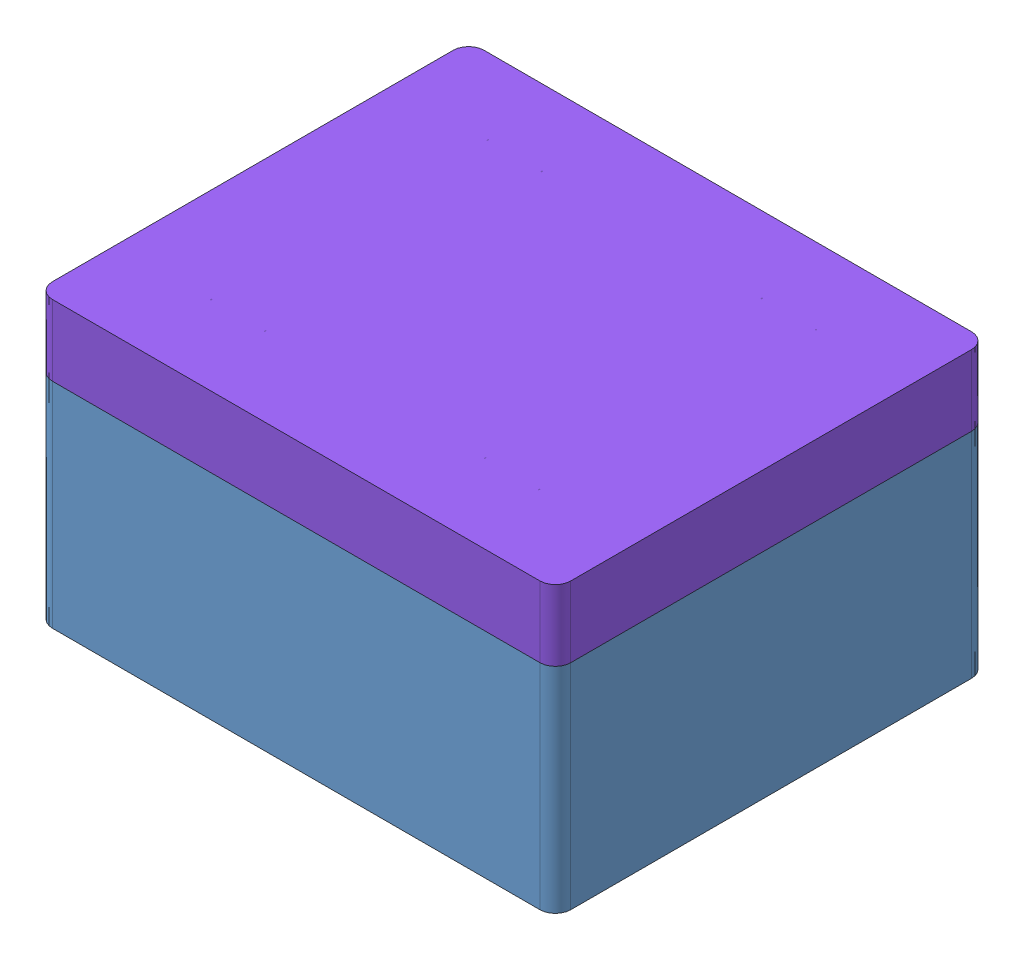
SolidWorks assembly LCA_Baseline_Enclosure_16122020, configuration Default. Lengths in mm.
Overall size (428.6 235.47 356.89).
8 component instances, 8 part files, 23 mates.
Components (placement in the parent):
- 1507 Bottom Tub-1: 1507 Bottom Tub [Default] at (199.2394 311.5225 306.9874) size (428.6 178.19 356.89)
- Back_Plate-1: Back_Plate [Default] at (199.2394 146.6765 306.9874) size (355.6 12.7 254)
- 8961K93_MOUNTING ADAPTERS FOR DIN RAIL-2-1: 8961K93_MOUNTING ADAPTERS FOR DIN RAIL-2 [8961K93] at (377.0394 159.3765 306.9874) x (0 -1 0) z (-1 0 0) size (7.5 35 355.6)
- 8961K107_MOUNTING ADAPTERS FOR DIN RAIL-1: 8961K107_MOUNTING ADAPTERS FOR DIN RAIL [8961K107] at (247.9771 169.3765 281.8198) x (0 1 0) z (-1 0 0) size (8 51.36 75)
- BaselineSpeedgoat-1: BaselineSpeedgoat [Default] at (192.9771 169.3765 270.6428) x (0 0 1) z (-1 0 0) size (200 130 190)
- LoadCellAmplifier-1: LoadCellAmplifier [Default] at (36.9078 238.5439 298.0974) x (-0.034899 0.999391 0) z (0.999391 0.034899 0) size (110.24 17.78 89.92)
- 8961K93_MOUNTING ADAPTERS FOR DIN RAIL 6in-1: 8961K93_MOUNTING ADAPTERS FOR DIN RAIL 6in [8961K93] at (4.1417 237.3997 383.1874) x (-0.999391 -0.034899 0) z (0 0 -1) size (7.5 35 152.4)
- 1507 Top Tub-1: 1507 Top Tub [Default] at (199.2394 311.5225 306.9874) size (428.6 59.13 356.89)
Mates (geometry in assembly coordinates):
- Coincident1: coincident anti-aligned: plane of 1507 Bottom Tub-1 through (63.4463 146.6765 182.6385) normal (0 1 0); plane of Back_Plate-1 through (199.2394 146.6765 306.9874) normal (0 -1 0)
- Width1: width aligned: plane of Back_Plate-1 through (21.4394 159.3765 179.9874) normal (-1 0 0); plane of Back_Plate-1 through (377.0394 159.3765 179.9874) normal (1 0 0); plane of 1507 Bottom Tub-1 through (1.794 304.6275 306.9874) normal (0.999391 0.034899 0); plane of 1507 Bottom Tub-1 through (396.6848 304.6275 306.9874) normal (-0.999391 0.034899 0)
- Width2: width anti-aligned: plane of Back_Plate-1 through (21.4394 159.3765 433.9874) normal (0 0 1); plane of Back_Plate-1 through (21.4394 159.3765 179.9874) normal (0 0 -1); plane of 1507 Bottom Tub-1 through (199.2394 306.2992 157.4134) normal (0 0.034899 0.999391); plane of 1507 Bottom Tub-1 through (199.2394 306.2992 456.5613) normal (0 0.034899 -0.999391)
- Coincident2: coincident anti-aligned: plane of Back_Plate-1 through (199.2394 159.3765 306.9874) normal (0 1 0); plane of 8961K93_MOUNTING ADAPTERS FOR DIN RAIL-2-1 through (-72.2231 159.3765 293.4874) normal (0 -1 0)
- Width3: width aligned: plane of 8961K93_MOUNTING ADAPTERS FOR DIN RAIL-2-1 through (377.0394 159.3765 306.9874) normal (1 0 0); plane of 8961K93_MOUNTING ADAPTERS FOR DIN RAIL-2-1 through (21.4394 159.3765 306.9874) normal (-1 0 0); plane of 1507 Bottom Tub-1 through (396.6848 304.6275 306.9874) normal (-0.999391 0.034899 0); plane of 1507 Bottom Tub-1 through (1.794 304.6275 306.9874) normal (0.999391 0.034899 0)
- Width4: width anti-aligned: plane of 8961K107_MOUNTING ADAPTERS FOR DIN RAIL-1 through (247.9771 163.0307 281.8198) normal (0 0 -1); plane of 8961K107_MOUNTING ADAPTERS FOR DIN RAIL-1 through (247.9771 165.6765 332.1549) normal (0 0 1); plane of 8961K93_MOUNTING ADAPTERS FOR DIN RAIL-2-1 through (-72.2231 166.8765 324.4874) normal (0 0 1); plane of 8961K93_MOUNTING ADAPTERS FOR DIN RAIL-2-1 through (-72.2231 165.8765 289.4874) normal (0 0 -1)
- Coincident3: coincident anti-aligned: plane of 8961K93_MOUNTING ADAPTERS FOR DIN RAIL-2-1 through (-72.2231 166.8765 320.4874) normal (0 1 0); plane of 8961K107_MOUNTING ADAPTERS FOR DIN RAIL-1 through (247.9771 166.8765 321.4049) normal (0 -1 0)
- Coincident4: coincident anti-aligned: plane of 8961K107_MOUNTING ADAPTERS FOR DIN RAIL-1 through (247.9771 169.3765 282.0698) normal (0 1 0); plane of BaselineSpeedgoat-1 through (192.9771 169.3765 270.6428) normal (0 -1 0)
- Perpendicular1: perpendicular: plane of 1507 Bottom Tub-1 through (199.2394 306.2992 157.4134) normal (0 0.034899 0.999391); plane of BaselineSpeedgoat-1 through (152.9771 299.3765 212.9874) normal (-1 0 0)
- Coincident6: coincident anti-aligned: plane of 8961K107_MOUNTING ADAPTERS FOR DIN RAIL-1 through (247.9771 169.3765 282.0698) normal (0 1 0); plane of BaselineSpeedgoat-1 through (192.9771 169.3765 270.6428) normal (0 -1 0)
- Width6: width anti-aligned: plane of BaselineSpeedgoat-1 through (342.9771 299.3765 402.9874) normal (0 0 1); plane of BaselineSpeedgoat-1 through (192.9771 169.3765 210.9874) normal (0 0 -1); plane of 1507 Bottom Tub-1 through (199.2394 306.2992 157.4134) normal (0 0.034899 0.999391); plane of 1507 Bottom Tub-1 through (199.2394 306.2992 456.5613) normal (0 0.034899 -0.999391)
- Width7: width aligned: plane of 8961K93_MOUNTING ADAPTERS FOR DIN RAIL-2-1 through (-72.2231 166.8765 324.4874) normal (0 0 1); plane of 8961K93_MOUNTING ADAPTERS FOR DIN RAIL-2-1 through (-72.2231 165.8765 289.4874) normal (0 0 -1); plane of 1507 Bottom Tub-1 through (199.2394 306.2992 456.5613) normal (0 0.034899 -0.999391); plane of 1507 Bottom Tub-1 through (199.2394 306.2992 157.4134) normal (0 0.034899 0.999391)
- Width8: width anti-aligned: plane of 8961K107_MOUNTING ADAPTERS FOR DIN RAIL-1 through (210.4771 166.4764 308.0981) normal (-1 0 0); plane of 8961K107_MOUNTING ADAPTERS FOR DIN RAIL-1 through (285.4771 166.4764 308.0981) normal (1 0 0); plane of BaselineSpeedgoat-1 through (342.9771 299.3765 212.9874) normal (1 0 0); plane of BaselineSpeedgoat-1 through (152.9771 299.3765 212.9874) normal (-1 0 0)
- Width9: width aligned: plane of 8961K93_MOUNTING ADAPTERS FOR DIN RAIL 6in-1 through (4.1417 237.3997 383.1874) normal (0 0 1); plane of 8961K93_MOUNTING ADAPTERS FOR DIN RAIL 6in-1 through (4.1417 237.3997 230.7874) normal (0 0 -1); plane of 1507 Bottom Tub-1 through (199.2394 306.2992 456.5613) normal (0 0.034899 -0.999391); plane of 1507 Bottom Tub-1 through (199.2394 306.2992 157.4134) normal (0 0.034899 0.999391)
- Coincident9: coincident anti-aligned: plane of 1507 Bottom Tub-1 through (199.2394 311.5225 306.9874) normal (0 1 0); plane of 1507 Top Tub-1 through (199.2394 311.5225 306.9874) normal (0 -1 0)
- Width12: width anti-aligned: plane of 1507 Top Tub-1 through (413.538 331.8425 129.797) normal (1 0 0); plane of 1507 Bottom Tub-1 through (-15.0592 331.8425 486.6911) normal (-1 0 0); plane of 1507 Top Tub-1 through (-15.0592 291.2025 129.797) normal (-1 0 0); plane of 1507 Bottom Tub-1 through (413.538 291.2025 486.6911) normal (1 0 0)
- Width13: width anti-aligned: plane of 1507 Top Tub-1 through (-15.0592 331.8425 129.797) normal (0 0 -1); plane of 1507 Bottom Tub-1 through (413.538 331.8425 486.6911) normal (0 0 1); plane of 1507 Top Tub-1 through (-15.0592 291.2025 486.6911) normal (0 0 1); plane of 1507 Bottom Tub-1 through (413.538 291.2025 129.797) normal (0 0 -1)
- Width19: width aligned: plane of LoadCellAmplifier-1 through (36.9078 238.5439 298.0974) normal (0 0 -1); plane of 8961K93_MOUNTING ADAPTERS FOR DIN RAIL 6in-1 through (36.9078 238.5439 315.8774) normal (0 0 1); plane of LoadCellAmplifier-1 through (4.1417 237.3997 230.7874) normal (0 0 -1); plane of 8961K93_MOUNTING ADAPTERS FOR DIN RAIL 6in-1 through (4.1417 237.3997 383.1874) normal (0 0 1)
- Coincident19: coincident anti-aligned: plane of LoadCellAmplifier-1 through (13.5607 182.577 315.8774) normal (-0.999391 -0.034899 0); plane of 8961K93_MOUNTING ADAPTERS FOR DIN RAIL 6in-1 through (12.1082 224.1696 -66.0751) normal (0.999391 0.034899 0)
- Width21: width aligned: plane of LoadCellAmplifier-1 through (9.7135 292.7458 315.8774) normal (-0.034899 0.999391 0); plane of 8961K93_MOUNTING ADAPTERS FOR DIN RAIL 6in-1 through (13.5607 182.577 315.8774) normal (0.034899 -0.999391 0); plane of LoadCellAmplifier-1 through (11.0264 255.1508 -66.0751) normal (-0.034899 0.999391 0); plane of 8961K93_MOUNTING ADAPTERS FOR DIN RAIL 6in-1 through (11.2485 220.1372 -66.0751) normal (0.034899 -0.999391 0)
- Coincident29: coincident anti-aligned: plane of 1507 Bottom Tub-1 through (1.794 304.6275 306.9874) normal (0.999391 0.034899 0); plane of 8961K93_MOUNTING ADAPTERS FOR DIN RAIL 6in-1 through (4.6128 223.9079 -66.0751) normal (-0.999391 -0.034899 0)
- Distance5: distance = 38.1 mm: line of 1507 Bottom Tub-1 through (1.5532 311.5225 412.9158) axis (0 0 -1); plane of LoadCellAmplifier-1 through (100.2396 276.8455 298.0974) normal (-0.034899 0.999391 0)
- Width26: width aligned: plane of BaselineSpeedgoat-1 through (152.9771 299.3765 212.9874) normal (-1 0 0); plane of LoadCellAmplifier-1 through (342.9771 299.3765 212.9874) normal (1 0 0); plane of BaselineSpeedgoat-1 through (103.4219 185.715 315.8774) normal (0.999391 0.034899 0); plane of 1507 Bottom Tub-1 through (396.6848 304.6275 306.9874) normal (-0.999391 0.034899 0)
